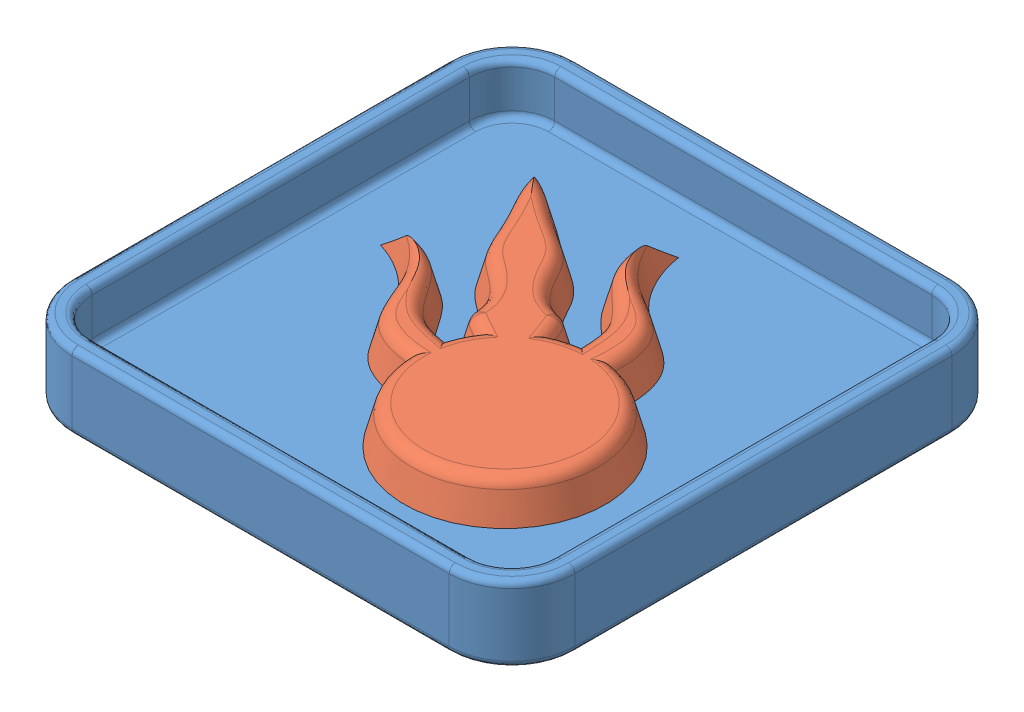
SolidWorks assembly Assem7, configuration Default. Lengths in mm.
Overall size (40 6 40).
2 component instances, 2 part files, 1 mates.
Components (placement in the parent):
- Tile-1: Tile [Default] at (15.3628 17.6767 30.6097) size (40 6 40)
- SolarFlare-1: SolarFlare [Default] at (20.3202 19.6767 36.124) x (0.756463 0 -0.654036) z (0.654036 0 0.756463) size (18.26 3.5 31.91)
Mates (geometry in assembly coordinates):
- Coincident1: coincident anti-aligned: plane of Tile-1 through (0.3628 19.6767 45.6097) normal (0 1 0); plane of SolarFlare-1 through (20.3202 19.6767 36.124) normal (0 -1 0)
